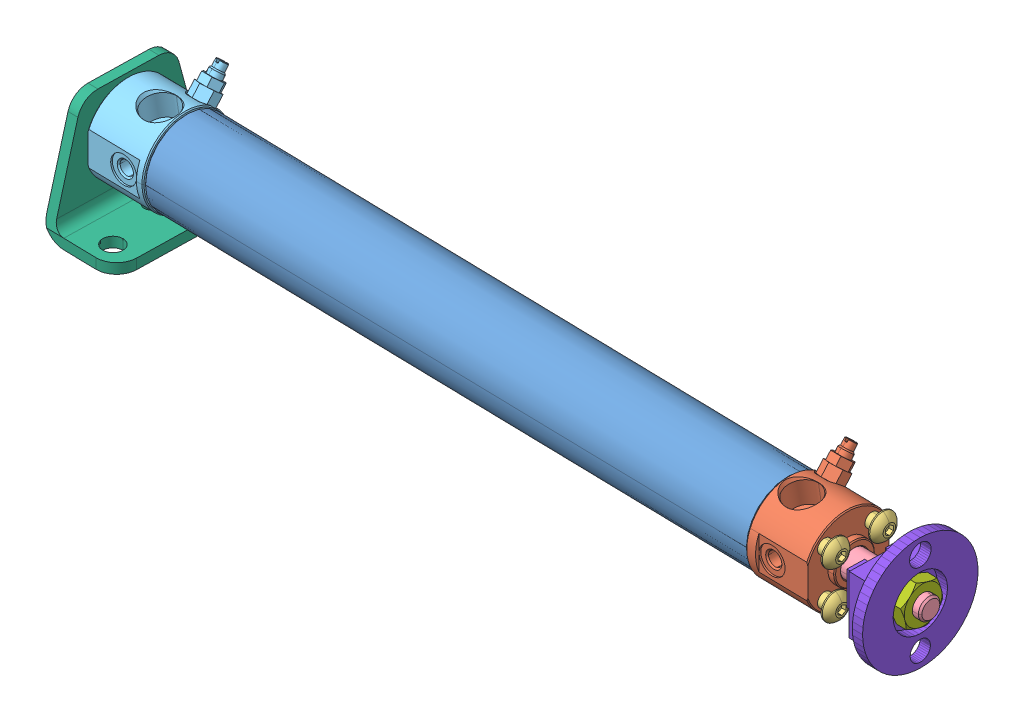
SolidWorks assembly piston_assembly, configuration Default. Lengths in mm.
Overall size (253.11 38.11 49.39).
16 component instances, 8 part files, 4 mates.
Components (placement in the parent):
- OCG13_4x6_Closed_Retract__86993_01_F_86993_01_R-1: OCG13_4x6_Closed_Retract__86993_01_F_86993_01_R [Default] at (515.5695 438.278 1234.7753) x (0.021645 0 -0.999766) z (0.999766 0 0.021645) size (43.94 38.11 252.22)
  - _TUBE_OCG13_4x6_Closed_Retract__86993_01_F_86993_01_R_2-1: _TUBE_OCG13_4x6_Closed_Retract__86993_01_F_86993_01_R_2 [Default] at origin size (24.99 24.99 185.47)
  - _HD_OCG13_4x6_Closed_Retract_4-1: _HD_OCG13_4x6_Closed_Retract_4 [Default] at (0 0 92.7354) size (28.44 31 20.04)
  - _ocg_sbhcs_8_32x3_8_8-1: _ocg_sbhcs_8_32x3_8_8 [Default] at (6.985 6.985 113.792) x (-1 0 0) z (0 1 0) size (7.92 11.81 7.92)
  - _ocg_sbhcs_8_32x3_8_8-2: _ocg_sbhcs_8_32x3_8_8 [Default] at (-6.985 6.985 113.792) x (-1 0 0) z (0 1 0) size (7.92 11.81 7.92)
  - _ocg_sbhcs_8_32x3_8_8-3: _ocg_sbhcs_8_32x3_8_8 [Default] at (6.985 -6.985 113.792) x (-1 0 0) z (0 1 0) size (7.92 11.81 7.92)
  - _ocg_sbhcs_8_32x3_8_8-4: _ocg_sbhcs_8_32x3_8_8 [Default] at (-6.985 -6.985 113.792) x (-1 0 0) z (0 1 0) size (7.92 11.81 7.92)
  - _PR_OCG1_3_4x6_13-1: _PR_OCG1_3_4x6_13 [Default] at (0 0 123.444) size (19.02 19.02 228.89)
  - _CAP_OCG1_3_4_17-1: _CAP_OCG1_3_4_17 [Default] at (0 0 -92.7354) size (28.44 31 21.58)
  - _BASE_MOUNT_OCG1_3_4_86993_01_6-2: _BASE_MOUNT_OCG1_3_4_86993_01_6 [Default] at (0 0 -113.792) size (43.94 34.04 22.1)
  - _ocg_sbhcs_8_32x3_8_8-5: _ocg_sbhcs_8_32x3_8_8 [Default] at (-6.985 6.985 -113.792) x (1 0 0) z (0 1 0) size (7.92 11.81 7.92)
  - _ocg_sbhcs_8_32x3_8_8-6: _ocg_sbhcs_8_32x3_8_8 [Default] at (6.985 6.985 -113.792) x (1 0 0) z (0 1 0) size (7.92 11.81 7.92)
  - _ocg_sbhcs_8_32x3_8_8-7: _ocg_sbhcs_8_32x3_8_8 [Default] at (-6.985 -6.985 -113.792) x (1 0 0) z (0 1 0) size (7.92 11.81 7.92)
  - _ocg_sbhcs_8_32x3_8_8-8: _ocg_sbhcs_8_32x3_8_8 [Default] at (6.985 -6.985 -113.792) x (1 0 0) z (0 1 0) size (7.92 11.81 7.92)
- _PN1972_015_NUT1_4_28_UNF_15-1: _PN1972_015_NUT1_4_28_UNF_15 [Default] at (645.3331 438.278 1237.5847) x (0.999766 0 0.021645) z (0.02094 0.253094 -0.967215) size (3.98 12.85 14.33)
- 3dprint_solidworks-1: 3dprint_solidworks [Default] at (634.141 421.4434 1254.4218) x (0.021645 0 -0.999766) z (0.999766 0 0.021645) size (34 34 14)
Mates (geometry in assembly coordinates):
- Concentric5: concentric: cylinder of OCG13_4x6_Closed_Retract__86993_01_F_86993_01_R-1/_PR_OCG1_3_4x6_13-1 through (422.8495 438.278 1232.7679) axis (0.999766 0 0.021645) radius 3.175; cylinder of _PN1972_015_NUT1_4_28_UNF_15-1 through (649.2946 438.278 1237.6705) axis (-0.999766 0 -0.021645) radius 2.6835
- Distance1: distance = 3.175 mm: plane of 3dprint_solidworks-1 through (648.1377 421.4434 1254.7249) normal (0.999766 0 0.021645); plane of OCG13_4x6_Closed_Retract__86993_01_F_86993_01_R-1/_PR_OCG1_3_4x6_13-1 through (651.6816 438.278 1237.7221) normal (0.999766 0 0.021645)
- Width4: width: plane of 3dprint_solidworks-1 through (634.2627 421.4434 1248.8037) normal (-0.021645 0 0.999766); plane of 3dprint_solidworks-1 through (634.7586 421.4434 1225.8971) normal (0.021645 0 -0.999766); plane of OCG13_4x6_Closed_Retract__86993_01_F_86993_01_R-1/_CAP_OCG1_3_4_17-1 through (415.5997 442.2785 1244.0437) normal (-0.021645 0 0.999766); plane of OCG13_4x6_Closed_Retract__86993_01_F_86993_01_R-1/_CAP_OCG1_3_4_17-1 through (416.0945 440.7787 1221.189) normal (0.021645 0 -0.999766)
- Coincident74: coincident: plane of _PN1972_015_NUT1_4_28_UNF_15-1 through (645.3331 438.278 1237.5847) normal (-0.999766 0 -0.021645); plane of 3dprint_solidworks-1 through (644.9635 421.4434 1254.6561) normal (0.999766 0 0.021645)
